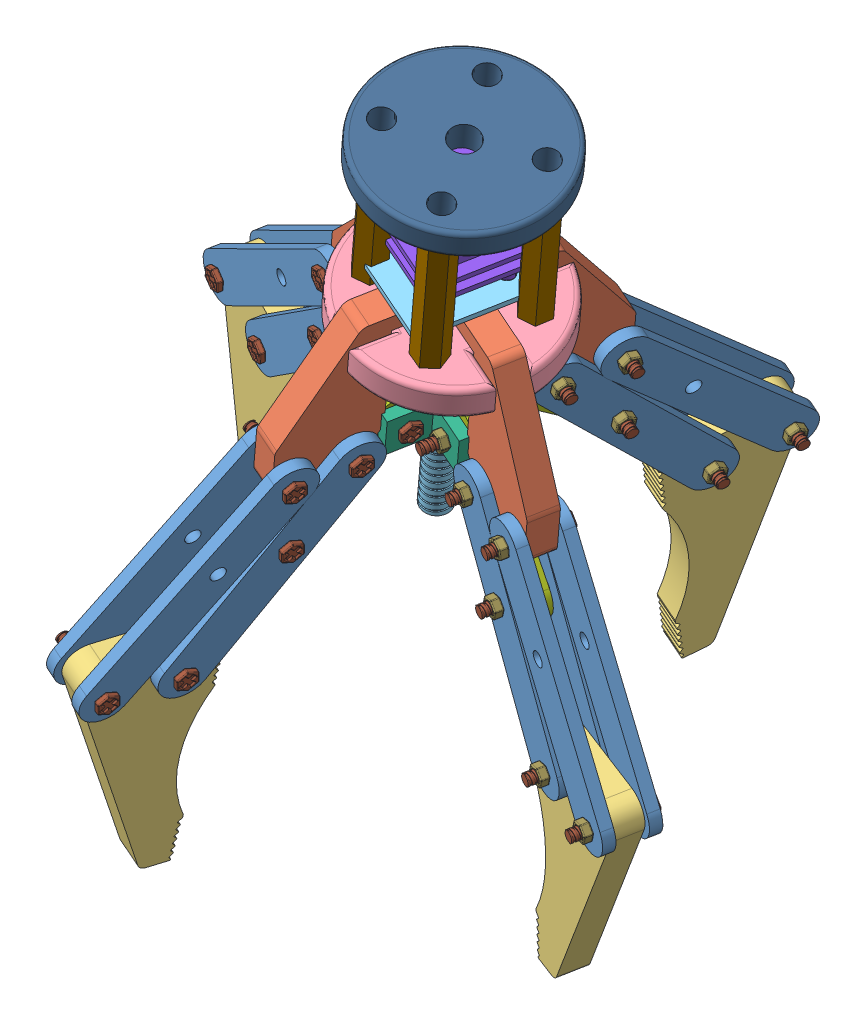
SolidWorks assembly Assem7, configuration Default. Lengths in mm.
Overall size (119.63 143.35 119.51).
85 component instances, 12 part files, 58 mates.
Components (placement in the parent):
- Part1-1: Part1 [Default] at (-32.46 156.4692 -145.5339) x (0.434894 -0.899402 0.044085) z (0.291395 0.09424 -0.951949) size (48 8 2)
- Part2-1: Part2 [Default] at (-34.4827 162.8591 -147.6214) x (-0.927278 0.272337 -0.256883) z (0.291395 0.09424 -0.951949) size (24 30 5)
- Part3-1: Part3 [Default] at (-11.8201 140.6217 -142.8857) x (0.950006 -0.145177 0.276428) z (0.291395 0.09424 -0.951949) size (21.78 45 5)
- Part4-1: Part4 [Default] at (-58.9212 198.4234 -154.2076) x (-0.927278 0.272337 -0.256883) z (0.235042 0.957576 0.166744) size (33.52 33.82 6)
- Part1-2: Part1 [Default] at (-30.4203 157.1289 -152.1975) x (0.434894 -0.899402 0.044085) z (0.291395 0.09424 -0.951949) size (48 8 2)
- Part1-3: Part1 [Default] at (-42.7965 158.702 -148.4769) x (0.381712 -0.923933 0.025377) z (0.291395 0.09424 -0.951949) size (48 8 2)
- Part1-4: Part1 [Default] at (-40.7567 159.3616 -155.1405) x (0.381712 -0.923933 0.025377) z (0.291395 0.09424 -0.951949) size (48 8 2)
- Part2-2: Part2 [Default] at (-77.5544 169.8377 -126.9844) x (0.291395 0.09424 -0.951949) z (0.927278 -0.272337 0.256883) size (24 30 5)
- Part2-3: Part2 [Default] at (-96.1522 181.8702 -169.869) x (0.927278 -0.272337 0.256883) z (-0.291395 -0.09424 0.951949) size (24 30 5)
- Part2-4: Part2 [Default] at (-53.0806 174.8916 -190.5061) x (-0.291395 -0.09424 0.951949) z (-0.927278 0.272337 -0.256883) size (24 30 5)
- Part1-5: Part1 [Default] at (-75.3725 163.0141 -122.6304) x (-0.36886 -0.781941 0.502504) z (0.927278 -0.272337 0.256883) size (48 8 2)
- Part1-6: Part1 [Default] at (-102.7039 177.4591 -167.0588) x (-0.788245 -0.540172 -0.29476) z (-0.291395 -0.09424 0.951949) size (48 8 2)
- Part1-7: Part1 [Default] at (-57.7517 171.574 -196.626) x (0.015509 -0.657632 -0.753179) z (-0.927278 0.272337 -0.256883) size (48 8 2)
- Part1-8: Part1 [Default] at (-72.3659 163.2969 -133.1835) x (-0.364229 -0.814921 0.450822) z (0.927278 -0.272337 0.256883) size (48 8 2)
- Part1-9: Part1 [Default] at (-92.7352 173.7284 -164.3767) x (-0.753448 -0.590542 -0.289095) z (-0.291395 -0.09424 0.951949) size (48 8 2)
- Part1-10: Part1 [Default] at (-61.126 169.7931 -186.3337) x (-0.007507 -0.699554 -0.71454) z (-0.927278 0.272337 -0.256883) size (48 8 2)
- Part1-11: Part1 [Default] at (-81.8634 164.9205 -124.4286) x (-0.36886 -0.781941 0.502504) z (0.927278 -0.272337 0.256883) size (48 8 2)
- Part1-12: Part1 [Default] at (-100.6641 178.1188 -173.7225) x (-0.788245 -0.540172 -0.29476) z (-0.291395 -0.09424 0.951949) size (48 8 2)
- Part1-13: Part1 [Default] at (-51.2608 169.6676 -194.8278) x (0.015509 -0.657632 -0.753179) z (-0.927278 0.272337 -0.256883) size (48 8 2)
- Part1-14: Part1 [Default] at (-78.8568 165.2033 -134.9817) x (-0.364229 -0.814921 0.450822) z (0.927278 -0.272337 0.256883) size (48 8 2)
- Part1-15: Part1 [Default] at (-90.6954 174.388 -171.0403) x (-0.753448 -0.590542 -0.289095) z (-0.291395 -0.09424 0.951949) size (48 8 2)
- Part1-16: Part1 [Default] at (-54.635 167.8868 -184.5355) x (-0.007507 -0.699554 -0.71454) z (-0.927278 0.272337 -0.256883) size (48 8 2)
- Part3-2: Part3 [Default] at (-89.3645 152.6381 -102.5873) x (-0.258267 0.0314 0.965563) z (0.927278 -0.272337 0.256883) size (21.78 45 5)
- Part3-3: Part3 [Default] at (-125.9497 175.0401 -179.6663) x (-0.888723 0.394848 -0.232953) z (-0.291395 -0.09424 0.951949) size (21.78 45 5)
- Part3-4: Part3 [Default] at (-48.4052 163.0236 -219.9648) x (0.31955 0.218272 -0.922087) z (-0.927278 0.272337 -0.256883) size (21.78 45 5)
- Part5-1: Part5 [Default] at (-56.8058 207.0416 -152.7069) x (0.291395 0.09424 -0.951949) z (0.235042 0.957576 0.166744) size (20 15 49.1)
- part7-1: part7 [Default] at (-61.6157 187.4458 -156.1191) x (0.291395 0.09424 -0.951949) z (-0.235042 -0.957576 -0.166744) size (22 22 7)
- Part6-1: Part6 [Default] at (-58.1244 177.9473 -172.9525) x (0.064137 -0.56046 -0.825694) z (0.368839 0.782124 -0.502235) size (31 3 8)
- Part6-2: Part6 [Default] at (-49.685 172.2954 -152.3912) x (0.542251 -0.836086 0.083215) z (0.788069 0.540444 0.294733) size (31 3 8)
- Part6-3: Part6 [Default] at (-70.3164 175.721 -142.9814) x (-0.374058 -0.702176 0.605829) z (-0.015387 0.657861 0.752982) size (31 3 8)
- Part6-4: Part6 [Default] at (-78.7558 181.3728 -163.5427) x (-0.852172 -0.426551 -0.30308) z (-0.434617 0.899541 -0.043986) size (31 3 8)
- part 8-1: part 8 [Default] at (-55.2335 215.4934 -151.8838) x (0.291395 0.09424 -0.951949) z (0.235042 0.957576 0.166744) size (16 14 20.6)
- part 9-1: part 9 [Default] at (-60.7953 231.3807 -142.9247) x (0.9337 -0.27011 0.235042) z (-0.235042 -0.957576 -0.166744) size (4.76 5.5 27)
- Part10-1: Part10 [Default] at (-49.9896 234.8113 -147.8713) x (0.9337 -0.27011 0.235042) z (-0.235042 -0.957576 -0.166744) size (32 32 5)
- part 9-2: part 9 [Default] at (-45.8561 227.059 -139.1641) x (0.27011 0.100444 -0.957576) z (-0.235042 -0.957576 -0.166744) size (4.76 5.5 27)
- part 9-3: part 9 [Default] at (-41.5343 228.6661 -154.4853) x (-0.9337 0.27011 -0.235042) z (-0.235042 -0.957576 -0.166744) size (4.76 5.5 27)
- part 9-4: part 9 [Default] at (-56.4735 232.9879 -158.246) x (-0.27011 -0.100444 0.957576) z (-0.235042 -0.957576 -0.166744) size (4.76 5.5 27)
- screw-1: screw [Default] at (-38.5354 175.3054 -154.9831) x (-0.76712 -0.571503 -0.291395) z (0.291395 0.09424 -0.951949) size (3.56 3.84 13)
- screw-2: screw [Default] at (-21.1396 139.3293 -153.2197) x (-0.76712 -0.571503 -0.291395) z (0.291395 0.09424 -0.951949) size (3.56 3.84 13)
- screw-3: screw [Default] at (-47.8081 178.0288 -157.552) x (-0.76712 -0.571503 -0.291395) z (0.291395 0.09424 -0.951949) size (3.56 3.84 13)
- screw-5: screw [Default] at (-63.2268 179.0506 -141.6862) x (0.00131 -0.683802 -0.729667) z (0.927278 -0.272337 0.256883) size (3.56 3.84 13)
- screw-6: screw [Default] at (-78.249 185.3507 -156.6909) x (0.402263 -0.914945 0.032558) z (-0.291395 -0.09424 0.951949) size (3.56 3.84 13)
- screw-7: screw [Default] at (-62.8304 184.3289 -172.5566) x (-0.366167 -0.802647 0.470829) z (-0.927278 0.272337 -0.256883) size (3.56 3.84 13)
- screw-8: screw [Default] at (-66.1407 178.1082 -132.1667) x (0.00131 -0.683802 -0.729667) z (0.927278 -0.272337 0.256883) size (3.56 3.84 13)
- screw-9: screw [Default] at (-87.5218 188.0741 -159.2597) x (0.402263 -0.914945 0.032558) z (-0.291395 -0.09424 0.951949) size (3.56 3.84 13)
- screw-10: screw [Default] at (-59.9164 185.2713 -182.0761) x (-0.366167 -0.802647 0.470829) z (-0.927278 0.272337 -0.256883) size (3.56 3.84 13)
- screw-11: screw [Default] at (-32.5397 141.0715 -156.5369) x (-0.76712 -0.571503 -0.291395) z (0.291395 0.09424 -0.951949) size (3.56 3.84 13)
- screw-12: screw [Default] at (-41.7007 163.2459 -157.1459) x (-0.76712 -0.571503 -0.291395) z (0.291395 0.09424 -0.951949) size (3.56 3.84 13)
- screw-13: screw [Default] at (-77.7959 146.4538 -123.6533) x (0.00131 -0.683802 -0.729667) z (0.927278 -0.272337 0.256883) size (3.56 3.84 13)
- screw-14: screw [Default] at (-108.3869 161.729 -168.2547) x (0.402263 -0.914945 0.032558) z (-0.291395 -0.09424 0.951949) size (3.56 3.84 13)
- screw-15: screw [Default] at (-63.1307 156.3467 -201.1383) x (-0.366167 -0.802647 0.470829) z (-0.927278 0.272337 -0.256883) size (3.56 3.84 13)
- screw-16: screw [Default] at (-80.8951 146.8306 -112.0666) x (0.00131 -0.683802 -0.729667) z (0.927278 -0.272337 0.256883) size (3.56 3.84 13)
- screw-17: screw [Default] at (-119.0516 166.4672 -171.0501) x (0.402263 -0.914945 0.032558) z (-0.291395 -0.09424 0.951949) size (3.56 3.84 13)
- screw-18: screw [Default] at (-59.2961 158.966 -212.2033) x (-0.366167 -0.802647 0.470829) z (-0.927278 0.272337 -0.256883) size (3.56 3.84 13)
- screw-19: screw [Default] at (-69.0544 166.0119 -134.4731) x (0.00131 -0.683802 -0.729667) z (0.927278 -0.272337 0.256883) size (3.56 3.84 13)
- screw-20: screw [Default] at (-90.3042 175.9021 -161.3164) x (0.402263 -0.914945 0.032558) z (-0.291395 -0.09424 0.951949) size (3.56 3.84 13)
- screw-21: screw [Default] at (-62.9505 173.136 -183.9893) x (-0.366167 -0.802647 0.470829) z (-0.927278 0.272337 -0.256883) size (3.56 3.84 13)
- nut-1: nut [Default] at (-74.4862 180.5593 -134.4787) x (-0.231696 0.121501 0.965171) z (-0.927278 0.272337 -0.256883) size (3 3.4 1.5)
- nut-2: nut [Default] at (-78.7908 168.8714 -137.1703) x (0.315892 0.200919 -0.927278) z (0.927278 -0.272337 0.256883) size (3 3.4 1.5)
- nut-3: nut [Default] at (-72.9632 181.9102 -144.3835) x (0.315892 0.200919 -0.927278) z (0.927278 -0.272337 0.256883) size (3 3.4 1.5)
- nut-4: nut [Default] at (-87.5323 149.3133 -126.3506) x (0.315892 0.200919 -0.927278) z (0.927278 -0.272337 0.256883) size (3 3.4 1.5)
- nut-5: nut [Default] at (-90.6315 149.6901 -114.7638) x (0.315892 0.200919 -0.927278) z (0.927278 -0.272337 0.256883) size (3 3.4 1.5)
- nut-6: nut [Default] at (-115.992 167.4567 -181.0456) x (0.947771 -0.16335 0.273945) z (-0.291395 -0.09424 0.951949) size (3 3.4 1.5)
- nut-7: nut [Default] at (-49.5597 156.1064 -209.506) x (-0.263231 0.013626 0.964637) z (-0.927278 0.272337 -0.256883) size (3 3.4 1.5)
- nut-8: nut [Default] at (-24.1992 138.3398 -143.2243) x (-0.89511 0.377895 -0.236586) z (0.291395 0.09424 -0.951949) size (3 3.4 1.5)
- nut-9: nut [Default] at (-75.1894 186.3403 -166.6864) x (0.947771 -0.16335 0.273945) z (-0.291395 -0.09424 0.951949) size (3 3.4 1.5)
- nut-10: nut [Default] at (-53.094 181.4693 -169.8594) x (-0.263231 0.013626 0.964637) z (-0.927278 0.272337 -0.256883) size (3 3.4 1.5)
- nut-11: nut [Default] at (-50.8678 177.0393 -147.5565) x (-0.89511 0.377895 -0.236586) z (0.291395 0.09424 -0.951949) size (3 3.4 1.5)
- nut-12: nut [Default] at (-84.8992 188.9223 -167.8273) x (-0.851591 0.478862 -0.21327) z (0.291395 0.09424 -0.951949) size (3 3.4 1.5)
- nut-13: nut [Default] at (-51.5709 182.8202 -179.7642) x (0.336442 0.305242 -0.890861) z (0.927278 -0.272337 0.256883) size (3 3.4 1.5)
- nut-14: nut [Default] at (-41.1579 174.4573 -146.4156) x (0.956338 -0.052118 0.287579) z (-0.291395 -0.09424 0.951949) size (3 3.4 1.5)
- nut-15: nut [Default] at (-105.3273 162.7186 -178.2502) x (0.947771 -0.16335 0.273945) z (-0.291395 -0.09424 0.951949) size (3 3.4 1.5)
- nut-16: nut [Default] at (-53.3943 153.4872 -198.441) x (-0.263231 0.013626 0.964637) z (-0.927278 0.272337 -0.256883) size (3 3.4 1.5)
- nut-17: nut [Default] at (-35.5993 140.0819 -146.5414) x (-0.89511 0.377895 -0.236586) z (0.291395 0.09424 -0.951949) size (3 3.4 1.5)
- nut-18: nut [Default] at (-87.2445 176.8916 -171.3119) x (0.947771 -0.16335 0.273945) z (-0.291395 -0.09424 0.951949) size (3 3.4 1.5)
- nut-19: nut [Default] at (-53.2141 170.2765 -181.292) x (-0.263231 0.013626 0.964637) z (-0.927278 0.272337 -0.256883) size (3 3.4 1.5)
- nut-20: nut [Default] at (-44.7604 162.2563 -147.1505) x (-0.89511 0.377895 -0.236586) z (0.291395 0.09424 -0.951949) size (3 3.4 1.5)
- screw-22: screw [Default] at (-54.3182 182.4287 -158.5839) x (-0.76712 -0.571503 -0.291395) z (0.291395 0.09424 -0.951949) size (3.56 3.84 13)
- nut-22: nut [Default] at (-57.0865 181.5334 -149.5404) x (0.874595 0.376884 0.305027) z (0.291395 0.09424 -0.951949) size (3 3.4 1.5)
- nut-23: nut [Default] at (-69.7239 184.8853 -150.976) x (-0.084146 0.516995 0.851843) z (0.927278 -0.272337 0.256883) size (3 3.4 1.5)
- nut-24: nut [Default] at (-67.7903 186.6551 -163.8651) x (-0.584401 0.805384 -0.099157) z (-0.291395 -0.09424 0.951949) size (3 3.4 1.5)
- nut-25: nut [Default] at (-55.1529 183.3032 -162.4295) x (0.374341 0.665274 -0.645972) z (-0.927278 0.272337 -0.256883) size (3 3.4 1.5)
- screw-23: screw [Default] at (-60.9147 182.2981 -148.5356) x (0.00131 -0.683802 -0.729667) z (0.927278 -0.272337 0.256883) size (3.56 3.84 13)
- screw-24: screw [Default] at (-70.5585 185.7598 -154.8216) x (0.402263 -0.914945 0.032558) z (-0.291395 -0.09424 0.951949) size (3.56 3.84 13)
- screw-25: screw [Default] at (-63.962 185.8904 -164.8699) x (-0.366167 -0.802647 0.470829) z (-0.927278 0.272337 -0.256883) size (3.56 3.84 13)
Mates (geometry in assembly coordinates):
- Coincident2: coincident anti-aligned: plane of Part2-1 through (-47.0461 201.5449 -152.8897) normal (-0.927278 0.272337 -0.256883); plane of Part4-1 through (-36.8351 204.8472 -186.2474) normal (0.927278 -0.272337 0.256883)
- Coincident4: coincident anti-aligned: plane of Part2-1 through (-48.4563 195.7995 -153.8902) normal (0.235042 0.957576 0.166744); plane of Part4-1 through (-47.9818 201.9613 -189.9451) normal (-0.235042 -0.957576 -0.166744)
- Coincident5: coincident anti-aligned: plane of Part2-1 through (-39.5491 170.7256 -148.3935) normal (-0.291395 -0.09424 0.951949); plane of Part4-1 through (-58.2394 203.9333 -150.8272) normal (0.291395 0.09424 -0.951949)
- Coincident6: coincident anti-aligned: plane of Part1-1 through (-40.5751 174.6457 -148.3195) normal (0.291395 0.09424 -0.951949); plane of Part2-1 through (-39.5491 170.7256 -148.3935) normal (-0.291395 -0.09424 0.951949)
- Concentric1: concentric aligned: circle of Part1-1; circle of Part2-1
- Concentric2: concentric aligned: circle of Part2-1; circle of Part1-2
- Coincident7: coincident anti-aligned: plane of Part2-1 through (-38.0921 171.1968 -153.1532) normal (0.291395 0.09424 -0.951949); plane of Part1-2 through (-39.1181 175.1169 -153.0792) normal (-0.291395 -0.09424 0.951949)
- Coincident8: coincident anti-aligned: plane of Part3-1 through (-67.4595 126.5904 -166.5586) normal (0.291395 0.09424 -0.951949); plane of Part1-2 through (-39.1181 175.1169 -153.0792) normal (-0.291395 -0.09424 0.951949)
- Concentric3: concentric aligned: circle of Part3-1; circle of Part1-2
- Concentric4: concentric aligned: circle of Part1-1; circle of Part3-1
- Coincident10: coincident anti-aligned: plane of Part2-1 through (-38.0921 171.1968 -153.1532) normal (0.291395 0.09424 -0.951949); plane of Part1-4
- Concentric5: concentric aligned: circle of Part2-1; circle of Part1-4
- Concentric6: concentric aligned: circle of Part3-1; circle of Part1-4
- Coincident11: coincident anti-aligned: plane of Part2-1 through (-39.5491 170.7256 -148.3935) normal (-0.291395 -0.09424 0.951949); plane of Part1-3
- Coincident12: coincident anti-aligned: plane of Part2-1 through (-39.5491 170.7256 -148.3935) normal (-0.291395 -0.09424 0.951949); plane of Part1-3
- Concentric7: concentric aligned: circle of Part2-1; circle of Part1-3
- Concentric8: concentric anti-aligned: circle of Part3-1; cylinder of Part1-3 through (-34.5794 140.4118 -149.8732) axis (-0.291395 -0.09424 0.951949) radius 1.25
- Coincident13: coincident anti-aligned: plane of Part2-2 through (-58.8586 204.9472 -137.7854) normal (0.235042 0.957576 0.166744); plane of Part5-1 through (-66.6744 208.1417 -145.114) normal (-0.235042 -0.957576 -0.166744)
- Concentric10: concentric aligned: circle of Part4-1; circle of Part5-1
- Parallel1: parallel aligned: line of Part2-3 through (-69.0415 211.0847 -158.6782) axis (-0.291395 -0.09424 0.951949); line of Part5-1 through (-60.6114 210.9841 -163.9862) axis (-0.291395 -0.09424 0.951949)
- Parallel2: parallel anti-aligned: plane of Part4-1 through (-47.9818 201.9613 -189.9451) normal (-0.235042 -0.957576 -0.166744); plane of part7-1 through (-68.6104 191.4781 -169.4163) normal (0.235042 0.957576 0.166744)
- Tangent1: tangent: face of Part4-1; cylinder of part7-1 through (-61.6157 187.4458 -156.1191) axis (-0.235042 -0.957576 -0.166744) radius 2.5
- Distance1: distance = 0.5 mm anti-aligned: plane of Part6-1 through (-57.3868 171.502 -182.448) normal (0.927278 -0.272337 0.256883); plane of part7-1 through (-60.0333 186.8131 -154.7164) normal (-0.927278 0.272337 -0.256883)
- Concentric11: concentric aligned: circle of part7-1; circle of Part6-1
- Parallel3: parallel anti-aligned: plane of Part3-2 through (-80.8316 128.5446 -158.9318) normal (-0.927278 0.272337 -0.256883); plane of Part6-1 through (-57.3868 171.502 -182.448) normal (0.927278 -0.272337 0.256883)
- Concentric12: concentric aligned: circle of Part1-16; circle of Part6-1
- Parallel4: parallel anti-aligned: plane of Part5-1 through (-66.4393 209.0993 -144.9473) normal (0.235042 0.957576 0.166744); plane of part 8-1 through (-47.3516 210.5106 -158.3682) normal (-0.235042 -0.957576 -0.166744)
- Coincident15: coincident anti-aligned: circle of part 8-1; plane of Part5-1 through (-51.7124 207.765 -157.4439) normal (0.235042 0.957576 0.166744)
- Concentric13: concentric anti-aligned: cylinder of Part5-1 through (-51.7124 207.765 -157.4439) axis (-0.235042 -0.957576 -0.166744) radius 1.375; cylinder of part 8-1 through (-51.7124 207.765 -157.4439) axis (0.235042 0.957576 0.166744) radius 1.373
- Parallel5: parallel anti-aligned: line of Part5-1 through (-52.5302 205.0142 -141.094) axis (0.291395 0.09424 -0.951949); line of part 8-1 through (-47.3516 210.5106 -158.3682) axis (-0.291395 -0.09424 0.951949)
- Coincident16: coincident anti-aligned: plane of part 9-1 through (-60.0525 231.657 -145.5581) normal (0.235042 0.957576 0.166744); plane of Part10-1 through (-41.6187 233.5733 -182.5471) normal (-0.235042 -0.957576 -0.166744)
- Concentric14: concentric aligned: circle of part 9-1; circle of Part10-1
- Concentric15: concentric aligned: circle of Part10-1; circle of Part4-1
- Distance2: distance = 27 mm anti-aligned: plane of Part10-1 through (-41.6187 233.5733 -182.5471) normal (-0.235042 -0.957576 -0.166744); plane of Part4-1 through (-46.5716 207.7068 -188.9446) normal (0.235042 0.957576 0.166744)
- Coincident17: coincident anti-aligned: plane of screw-1 through (-37.2632 173.8327 -154.7395) normal (-0.291395 -0.09424 0.951949); plane of Part1-2 through (-38.5354 175.3054 -154.9831) normal (0.291395 0.09424 -0.951949)
- Concentric16: concentric aligned: circle of Part1-2; circle of screw-1
- Coincident18: coincident anti-aligned: plane of screw-3 through (-46.536 176.5561 -157.3084) normal (-0.291395 -0.09424 0.951949); plane of Part1-4
- Concentric17: concentric aligned: circle of Part1-4; circle of screw-3
- Coincident21: coincident anti-aligned: plane of screw-2 through (-19.8675 137.8566 -152.9761) normal (-0.291395 -0.09424 0.951949); plane of Part1-2 through (-38.5354 175.3054 -154.9831) normal (0.291395 0.09424 -0.951949)
- Coincident22: coincident anti-aligned: plane of screw-11 through (-31.2675 139.5987 -156.2933) normal (-0.291395 -0.09424 0.951949); plane of Part1-2 through (-38.5354 175.3054 -154.9831) normal (0.291395 0.09424 -0.951949)
- Coincident23: coincident anti-aligned: plane of screw-12 through (-40.4286 161.7731 -156.9023) normal (-0.291395 -0.09424 0.951949); plane of Part1-4
- Concentric18: concentric aligned: circle of Part1-4; circle of screw-12
- Concentric19: concentric aligned: circle of Part1-2; circle of screw-2
- Concentric20: concentric aligned: circle of Part1-4; circle of screw-11
- Coincident24: coincident anti-aligned: plane of Part1-11; plane of nut-1 through (-74.9955 178.906 -134.3928) normal (0.927278 -0.272337 0.256883)
- Concentric21: concentric aligned: circle of nut-1; circle of Part1-11
- Coincident25: coincident anti-aligned: plane of Part1-14; plane of nut-3 through (-71.9203 179.8718 -144.4699) normal (0.927278 -0.272337 0.256883)
- Concentric22: concentric anti-aligned: circle of Part1-14; circle of nut-3
- Coincident26: coincident anti-aligned: plane of Part1-11; plane of nut-2 through (-77.7479 166.8331 -137.2567) normal (0.927278 -0.272337 0.256883)
- Concentric23: concentric anti-aligned: circle of Part1-14; circle of nut-2
- Coincident28: coincident anti-aligned: plane of Part1-14; plane of nut-4 through (-86.4894 147.275 -126.437) normal (0.927278 -0.272337 0.256883)
- Concentric24: concentric anti-aligned: circle of Part1-14; circle of nut-4
- Coincident29: coincident anti-aligned: plane of Part1-11; plane of nut-5 through (-89.5886 147.6518 -114.8502) normal (0.927278 -0.272337 0.256883)
- Concentric25: concentric anti-aligned: circle of Part1-11; circle of nut-5
- Coincident30: coincident anti-aligned: plane of screw-22 through (-53.0461 180.956 -158.3403) normal (-0.291395 -0.09424 0.951949); plane of part7-1 through (-50.2501 184.827 -157.1012) normal (0.291395 0.09424 -0.951949)
- Coincident31: coincident anti-aligned: circle of part7-1; circle of screw-22
- Coincident36: coincident anti-aligned: plane of part7-1 through (-52.5813 184.0731 -149.4856) normal (-0.291395 -0.09424 0.951949); plane of nut-22
- Concentric26: concentric aligned: circle of nut-22; circle of part7-1
